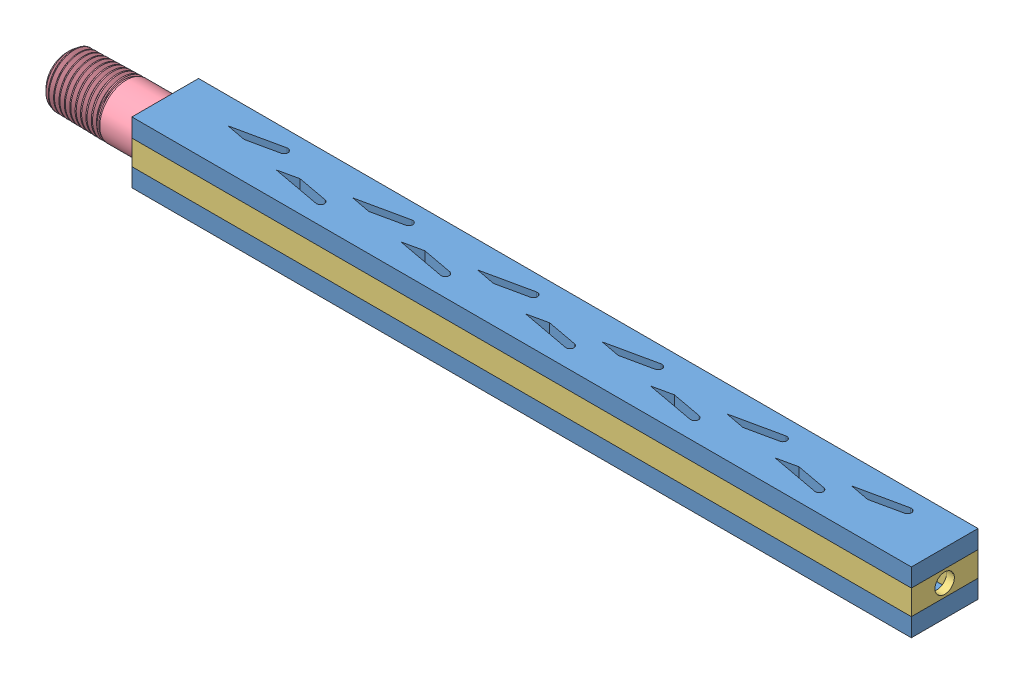
SolidWorks assembly valvular conduit, configuration Default. Lengths in mm.
Overall size (225.47 18.91 18.96).
15 component instances, 4 part files, 15 mates.
Components (placement in the parent):
- bottom-1: bottom [Default] at origin size (200 4.7 17.1)
- diverter-1: diverter [Default] at (42.1708 0 -5.3509) x (0.983115 0 0.182989) z (-0.182989 0 0.983115) size (13.35 12.7 1.6)
- diverter-2: diverter [Default] at (74.1708 0 -5.3509) x (0.983115 0 0.182989) z (-0.182989 0 0.983115) size (13.35 12.7 1.6)
- diverter-3: diverter [Default] at (106.1708 0 -5.3509) x (0.983115 0 0.182989) z (-0.182989 0 0.983115) size (13.35 12.7 1.6)
- diverter-4: diverter [Default] at (138.1708 0 -5.3509) x (0.983115 0 0.182989) z (-0.182989 0 0.983115) size (13.35 12.7 1.6)
- diverter-5: diverter [Default] at (170.1708 0 -5.3509) x (0.983115 0 0.182989) z (-0.182989 0 0.983115) size (13.35 12.7 1.6)
- diverter-6: diverter [Default] at (26.1697 12.7 -12.0762) x (0.977698 0 -0.210016) z (-0.210016 0 -0.977698) size (13.35 12.7 1.6)
- diverter-7: diverter [Default] at (58.1697 12.7 -12.0762) x (0.977698 0 -0.210016) z (-0.210016 0 -0.977698) size (13.35 12.7 1.6)
- diverter-8: diverter [Default] at (90.1697 12.7 -12.0762) x (0.977698 0 -0.210016) z (-0.210016 0 -0.977698) size (13.35 12.7 1.6)
- diverter-9: diverter [Default] at (122.1697 12.7 -12.0762) x (0.977698 0 -0.210016) z (-0.210016 0 -0.977698) size (13.35 12.7 1.6)
- diverter-10: diverter [Default] at (154.1697 12.7 -12.0762) x (0.977698 0 -0.210016) z (-0.210016 0 -0.977698) size (13.35 12.7 1.6)
- diverter-11: diverter [Default] at (186.1697 12.7 -12.0762) x (0.977698 0 -0.210016) z (-0.210016 0 -0.977698) size (13.35 12.7 1.6)
- channel-1: channel [Default] at (0 4.7 0) size (200 6.35 17.1)
- bottom-2: bottom [Default] at (0 11.05 0) size (200 4.7 17.1)
- 9157K110_STD-WALL 304-304L SS THRD ONE END PIPE NIPPLE-1: 9157K110_STD-WALL 304-304L SS THRD ONE END PIPE NIPPLE [9157K11] at (-12.7 7.875 -8.55) x (-1 0 0) z (0 -0.924225 -0.381849) size (25.47 14.55 14.44)
Mates (geometry in assembly coordinates):
- Coincident1: coordinate: point of bottom-1; point of assembly
- Coincident2: coincident anti-aligned: plane of bottom-1 through (42.817 -0.001 -4.4169) normal (0.182989 0 -0.983115); plane of diverter-1 through (42.0244 12.7 -4.5644) normal (-0.182989 0 0.983115)
- Coincident3: coincident aligned: plane of bottom-1 through (0 0 0) normal (0 -1 0); plane of diverter-1 through (42.1708 0 -5.3509) normal (0 -1 0)
- Coincident6: coincident aligned: plane of bottom-1 through (0 0 0) normal (0 -1 0); plane of diverter-6 through (26.1697 0 -12.0762) normal (0 -1 0)
- Coincident7: coincident anti-aligned: plane of bottom-1 through (26.79 -0.001 -13.0277) normal (0.210016 0 0.977698); plane of diverter-6 through (26.0017 0 -12.8584) normal (-0.210016 0 -0.977698)
- Coincident9: coincident aligned: plane of bottom-1 through (0 4.7 0) normal (0 0 1); plane of channel-1 through (0 11.05 0) normal (0 0 1)
- Coincident10: coincident aligned: plane of bottom-1 through (0 4.7 0) normal (-1 0 0); plane of channel-1 through (0 11.05 0) normal (-1 0 0)
- Coincident11: coincident anti-aligned: plane of bottom-1 through (0 4.7 0) normal (0 1 0); plane of channel-1 through (0 4.7 0) normal (0 -1 0)
- Coincident12: coincident aligned: plane of channel-1 through (0 11.05 0) normal (0 0 1); plane of bottom-2 through (0 15.75 0) normal (0 0 1)
- Coincident13: coincident aligned: plane of channel-1 through (0 11.05 0) normal (-1 0 0); plane of bottom-2 through (0 15.75 0) normal (-1 0 0)
- Coincident14: coincident anti-aligned: plane of channel-1 through (0 11.05 0) normal (0 1 0); plane of bottom-2 through (0 11.05 0) normal (0 -1 0)
- Concentric1: concentric aligned: cylinder of channel-1 through (200.001 7.875 -8.55) axis (-1 0 0) radius 2.5; cylinder of 9157K110_STD-WALL 304-304L SS THRD ONE END PIPE NIPPLE-1 through (0 7.875 -8.55) axis (-1 0 0) radius 4.6228
- Coincident15: coincident anti-aligned: plane of channel-1 through (0 11.05 0) normal (-1 0 0); plane of 9157K110_STD-WALL 304-304L SS THRD ONE END PIPE NIPPLE-1 through (0 7.875 -8.55) normal (1 0 0)
- Coincident19: coincident: plane of diverter-6 through (18.7312 0 -9.6601) normal (-0.111811 0 0.993729); moEndPointRef_w of bottom-2
- Coincident20: coincident: moEndPointRef_w of bottom-1; plane of diverter-1 through (34.6685 12.7 -7.5611) normal (-0.139157 0 -0.99027)
